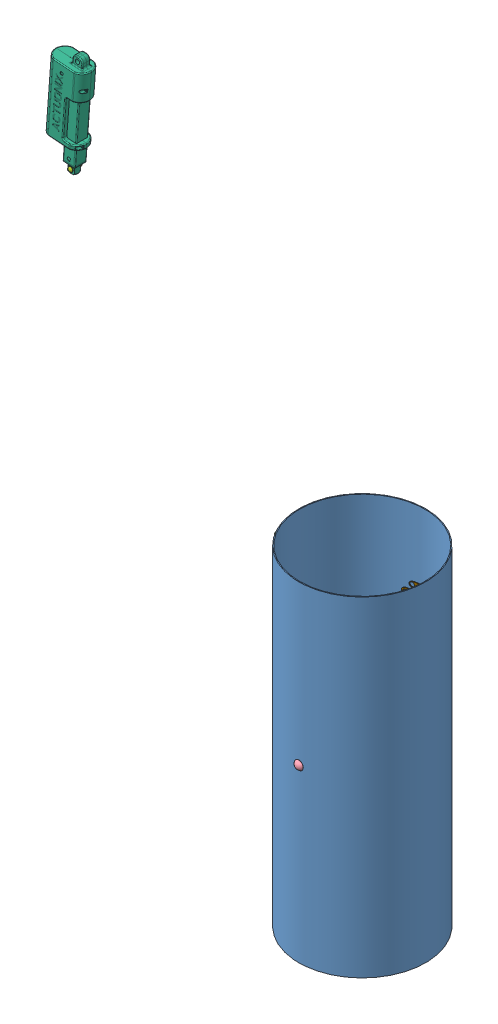
SolidWorks assembly Assembly, configuration Default. Lengths in mm.
Overall size (426.64 640.71 287.26).
12 component instances, 9 part files, 26 mates.
Components (placement in the parent):
- BodyTube-1: BodyTube [Default] at (109.2416 50.5743 310.056) size (249.72 389.15 287.26)
- EngineCasing-1: EngineCasing [Default] at (111.0859 50.6338 307.9911) x (0.00013 -0.012043 0.999927) z (-0.999942 -0.01076 0) size (29 186.69 29)
- GimbalRing-1: GimbalRing [Default] at (109.3437 212.537 310.056) x (0 0 -1) z (0.999942 0.01076 0) size (88.9 19.08 88.9)
- Quarter 20 bolt - Body Tube to Gimbal Ring - Copy-2: Quarter 20 bolt - Body Tube to Gimbal Ring - Copy [Default] at (109.2416 222.0243 370.254) x (-0.558878 -0.82925 0) z (0 0 1) size (8.89 8.89 25.15)
- Quarter 20 bolt - Body Tube to Gimbal Ring - Copy-4: Quarter 20 bolt - Body Tube to Gimbal Ring - Copy [Default] at (109.2416 222.0243 249.858) x (0.99453 0.104448 0) z (0 0 -1) size (8.89 8.89 25.15)
- Quarter 20 bolt - Gimbal Ring to Engine Casing-1: Quarter 20 bolt - Gimbal Ring to Engine Casing [Default] at (64.7718 221.5829 310.056) x (-0.007495 0.696478 -0.717539) z (0.999942 0.01076 0) size (10.16 10.16 33.11)
- Quarter 20 bolt - Gimbal Ring to Engine Casing-3: Quarter 20 bolt - Gimbal Ring to Engine Casing [Default] at (153.7107 222.54 310.056) x (0.010702 -0.994574 0.103475) z (-0.999942 -0.01076 0) size (10.16 10.16 33.11)
- p16_50mm_in(Actuator)-1: p16_50mm_in(Actuator) [Default] at (-163.2637 654.5579 308.5342) x (0.99723 -0.074373 0) z (-0.074373 -0.99723 0) size (36.18 20.01 105.9)
- Actuator Fastoning pin-1: Actuator Fastoning pin [Default] at (-180.6439 562.6961 303.4443) x (-0.188969 -0.981983 0) z (0 0 -1) size (4.83 4.83 11.76)
- Actuator Fastener Gimbal-1: Actuator Fastener Gimbal [Default] at (154.9906 234.422 308.0681) x (0 0 1) z (-0.999942 -0.01076 0) size (7.62 9.17 7.62)
- Actuator Fastoning pin-2: Actuator Fastoning pin [Default] at (34.9589 358.2457 312.0626) x (-0.860701 0.509111 0) z (0 0 -1) size (4.83 4.83 11.76)
- Actuator Fastener BodyTube-2: Actuator Fastener BodyTube [Default] at (166.6147 358.2763 302.5212) x (-0.155138 0 -0.987893) z (0 1 0) size (9.65 22.66 5.84)
Mates (geometry in assembly coordinates):
- Coincident3: coincident: plane of EngineCasing-1 through (111.0859 50.6338 307.9911) normal (-0.999942 -0.01076 0); plane of GimbalRing-1 through (109.3437 212.537 310.056) normal (0.999942 0.01076 0)
- Concentric5: concentric: cylinder of EngineCasing-1 through (95.377 221.9122 310.056) axis (-0.999942 -0.01076 0) radius 1.905; cylinder of GimbalRing-1 through (77.4931 221.7198 310.056) axis (-0.999942 -0.01076 0) radius 2.5527
- Coincident5: coincident: plane of BodyTube-1 through (109.2416 50.5743 310.056) normal (0 0 1); plane of GimbalRing-1 through (115.8716 220.2538 310.056) normal (0 0 -1)
- Concentric7: concentric: cylinder of GimbalRing-1 through (110.2147 227.8708 354.506) axis (0 0 -1) radius 1.905; cylinder of Quarter 20 bolt - Body Tube to Gimbal Ring - Copy-2 through (110.2147 227.8708 351.077) axis (0 0 1) radius 1.905
- Tangent1: tangent: cylinder of GimbalRing-1 through (109.1387 231.5859 310.056) axis (0.01076 -0.999942 0) radius 44.45; plane of Quarter 20 bolt - Body Tube to Gimbal Ring - Copy-2 through (109.2416 222.0243 354.506) normal (0 0 -1)
- Concentric8: concentric: cylinder of GimbalRing-1 through (110.2147 227.8708 354.506) axis (0 0 -1) radius 1.905; cylinder of Quarter 20 bolt - Body Tube to Gimbal Ring - Copy-4 through (109.2416 222.0243 269.035) axis (0 0 -1) radius 1.905
- Tangent2: tangent: cylinder of GimbalRing-1 through (109.1387 231.5859 310.056) axis (0.01076 -0.999942 0) radius 44.45; plane of Quarter 20 bolt - Body Tube to Gimbal Ring - Copy-4 through (109.2416 222.0243 265.606) normal (0 0 1)
- Concentric10: concentric: cylinder of EngineCasing-1 through (95.377 221.9122 310.056) axis (-0.999942 -0.01076 0) radius 1.905; cylinder of Quarter 20 bolt - Gimbal Ring to Engine Casing-1 through (95.377 221.9122 310.056) axis (-0.999942 -0.01076 0) radius 1.8415
- Concentric12: concentric: circle of EngineCasing-1; circle of Quarter 20 bolt - Gimbal Ring to Engine Casing-3
- Tangent5: tangent: circle of EngineCasing-1; plane of Quarter 20 bolt - Gimbal Ring to Engine Casing-3 through (123.1054 222.2106 310.056) normal (-0.999942 -0.01076 0)
- Coincident6: coincident: plane of EngineCasing-1 through (95.377 221.9122 310.056) normal (-0.999942 -0.01076 0); plane of Quarter 20 bolt - Gimbal Ring to Engine Casing-1 through (95.377 221.9122 310.056) normal (0.999942 0.01076 0)
- Concentric13: concentric: circle of p16_50mm_in(Actuator)-1; circle of Actuator Fastener Gimbal-1
- Concentric14: concentric: cylinder of p16_50mm_in(Actuator)-1 through (-180.6439 562.6961 313.0342) axis (0 0 -1) radius 2.125; cylinder of Actuator Fastoning pin-1 through (-180.6439 562.6961 312.3343) axis (0 0 -1) radius 2.032
- Coincident7: coincident: plane of Actuator Fastoning pin-1 through (-180.6439 562.6961 312.3343) normal (0 0 -1); plane of Actuator Fastener Gimbal-1 through (147.3957 232.0484 312.3343) normal (0 0 1)
- Distance1: distance = 0.1651 mm: plane of p16_50mm_in(Actuator)-1 through (-185.5331 557.6458 311.5342) normal (0 0 1); plane of Actuator Fastener Gimbal-1 through (147.2973 241.1918 311.6993) normal (0 0 -1)
- Coincident8: coincident: line of GimbalRing-1 through (153.5677 232.0894 311.3272) axis (0 0 -1); line of Actuator Fastener Gimbal-1 through (153.5677 232.0894 305.9825) axis (0 0 1)
- Coincident9: coincident: plane of GimbalRing-1 through (109.1385 231.6113 310.056) normal (-0.01076 0.999942 0); plane of Actuator Fastener Gimbal-1 through (155.0155 232.105 308.0681) normal (0.01076 -0.999942 0)
- Coincident10: coincident: line of GimbalRing-1 through (150.3915 232.0552 311.3272) axis (0.999942 0.01076 0); line of Actuator Fastener Gimbal-1 through (153.5677 232.0894 311.3272) axis (-0.999942 -0.01076 0)
- Concentric16: concentric: cylinder of p16_50mm_in(Actuator)-1 through (29.0553 361.1973 312.5342) axis (0 0 -1) radius 2.125; cylinder of Actuator Fastoning pin-2 through (29.0553 361.1973 313.348) axis (0 0 -1) radius 2.032
- Concentric18: concentric: cylinder of BodyTube-1 through (109.2416 222.0243 246.556) axis (0 0 -1) radius 2.5527; cylinder of Quarter 20 bolt - Body Tube to Gimbal Ring - Copy-4 through (109.2416 222.0243 265.606) axis (0 0 -1) radius 2.2225
- Concentric19: concentric: cylinder of BodyTube-1 through (109.2416 222.0243 373.556) axis (0 0 1) radius 2.5527; cylinder of Quarter 20 bolt - Body Tube to Gimbal Ring - Copy-2 through (109.2416 222.0243 354.506) axis (0 0 1) radius 2.2225
- Concentric20: concentric: cylinder of GimbalRing-1 through (109.2416 222.0243 354.506) axis (0 0 -1) radius 1.905; cylinder of Quarter 20 bolt - Body Tube to Gimbal Ring - Copy-4 through (109.2416 222.0243 269.035) axis (0 0 -1) radius 1.905
- Tangent9: tangent: cylinder of BodyTube-1 through (109.2416 380.7743 310.056) axis (0 -1 0) radius 63.5; plane of Quarter 20 bolt - Body Tube to Gimbal Ring - Copy-2 through (109.2416 222.0243 373.556) normal (0 0 -1)
- Tangent19: tangent: circle of BodyTube-1; circle of Actuator Fastener BodyTube-2
- Parallel1: parallel: plane of BodyTube-1 through (109.2416 380.7743 310.056) normal (0 1 0); plane of Actuator Fastener BodyTube-2 through (166.6147 364.1183 302.5212) normal (0 1 0)
- Parallel2: parallel: line of BodyTube-1 through (172.7416 414.6586 310.056) axis (0 -1 0); line of Actuator Fastener BodyTube-2 through (169.399 364.1183 305.479) axis (0 -1 0)
